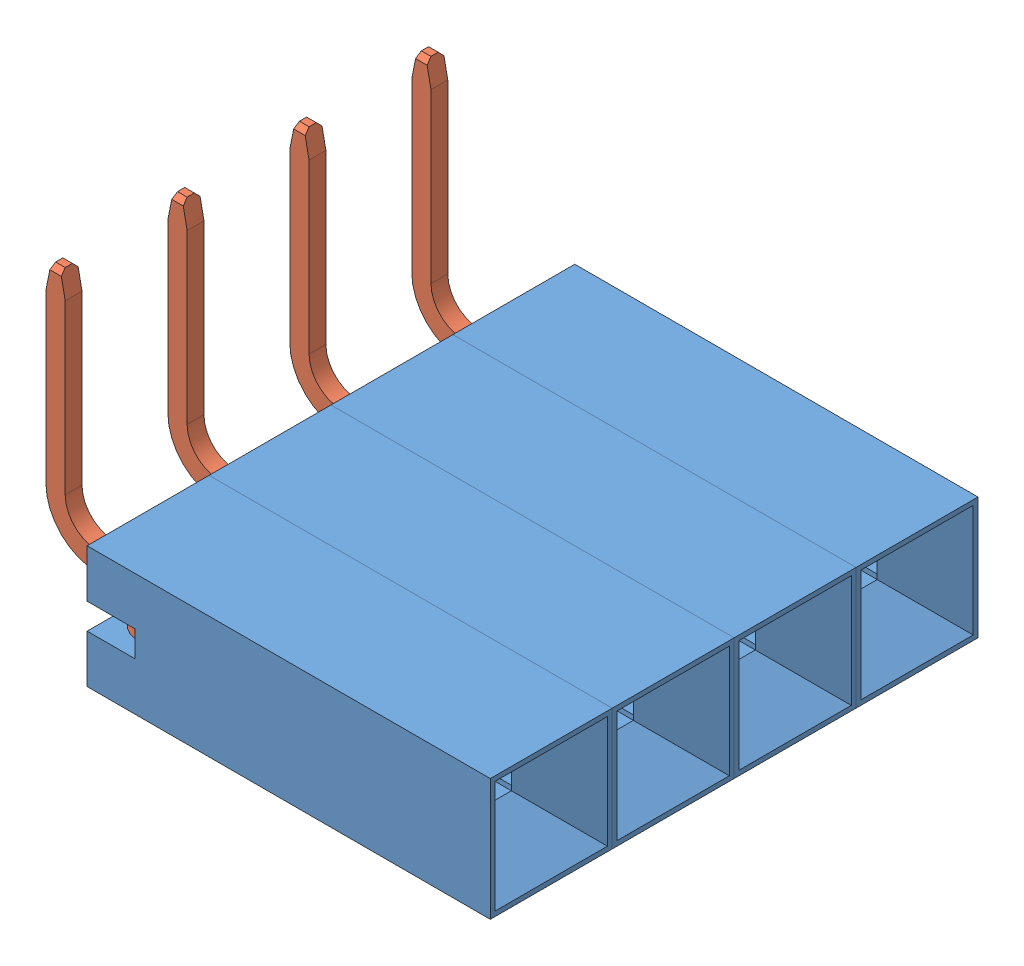
SolidWorks assembly H254_90deg_4pin, configuration Default. Lengths in mm.
Overall size (10.36 6.14 10.16).
12 component instances, 2 part files, 6 mates.
Components (placement in the parent):
- FrameAndPin_H254_90deg-1: FrameAndPin_H254_90deg [Default] at origin size (10.36 6.14 2.54)
  - frame_H254-1: frame_H254 [Default] at origin size (8.4 2.54 2.54)
  - pin-90deg-1: pin-90deg [Default] at (-0.0461 1.2682 1.27) x (0 0 -1) z (0.999998 -0.002105 0) size (1.95 5.07 7.58)
- FrameAndPin_H254_90deg-2: FrameAndPin_H254_90deg [Default] at (0 0 -2.54) size (10.36 6.14 2.54)
  - frame_H254-1: frame_H254 [Default] at origin size (8.4 2.54 2.54)
  - pin-90deg-1: pin-90deg [Default] at (-0.0461 1.2682 1.27) x (0 0 -1) z (0.999998 -0.002105 0) size (1.95 5.07 7.58)
- FrameAndPin_H254_90deg-4: FrameAndPin_H254_90deg [Default] at (0 0 -5.08) size (10.36 6.14 2.54)
  - frame_H254-1: frame_H254 [Default] at origin size (8.4 2.54 2.54)
  - pin-90deg-1: pin-90deg [Default] at (-0.0461 1.2682 1.27) x (0 0 -1) z (0.999998 -0.002105 0) size (1.95 5.07 7.58)
- FrameAndPin_H254_90deg-5: FrameAndPin_H254_90deg [Default] at (0 0 -7.62) size (10.36 6.14 2.54)
  - frame_H254-1: frame_H254 [Default] at origin size (8.4 2.54 2.54)
  - pin-90deg-1: pin-90deg [Default] at (-0.0461 1.2682 1.27) x (0 0 -1) z (0.999998 -0.002105 0) size (1.95 5.07 7.58)
Mates (geometry in assembly coordinates):
- Coincident1: coincident aligned: line of FrameAndPin_H254_90deg-1/frame_H254-1 through (8.4 8.4 2.54) axis (0 -1 0); line of FrameAndPin_H254_90deg-2/frame_H254-1 through (8.4 8.4 2.54) axis (0 -1 0)
- Coincident2: coincident aligned: line of FrameAndPin_H254_90deg-1/frame_H254-1 through (2.54 8.4 0) axis (0 0 1); line of FrameAndPin_H254_90deg-2/frame_H254-1 through (2.54 8.4 0) axis (0 0 1)
- Coincident3: coincident aligned: line of FrameAndPin_H254_90deg-2/frame_H254-1 through (8.4 2.54 -2.54) axis (-1 0 0); line of FrameAndPin_H254_90deg-4/frame_H254-1 through (8.4 2.54 -2.54) axis (-1 0 0)
- Coincident4: coincident aligned: line of FrameAndPin_H254_90deg-2/frame_H254-1 through (8.4 0 -2.54) axis (0 1 0); line of FrameAndPin_H254_90deg-4/frame_H254-1 through (8.4 0 -2.54) axis (0 1 0)
- Coincident5: coincident: plane of FrameAndPin_H254_90deg-4/frame_H254-1 through (0 0 -5.08) normal (0 0 -1); plane of FrameAndPin_H254_90deg-5/frame_H254-1 through (-0.1401 0.0331 -5.08) normal (0 0 1)
- Coincident7: coincident aligned: line of FrameAndPin_H254_90deg-4/frame_H254-1 through (8.4 2.54 -2.54) axis (0 0 -1); line of FrameAndPin_H254_90deg-5/frame_H254-1 through (8.2599 2.5731 -5.08) axis (0 0 -1)
